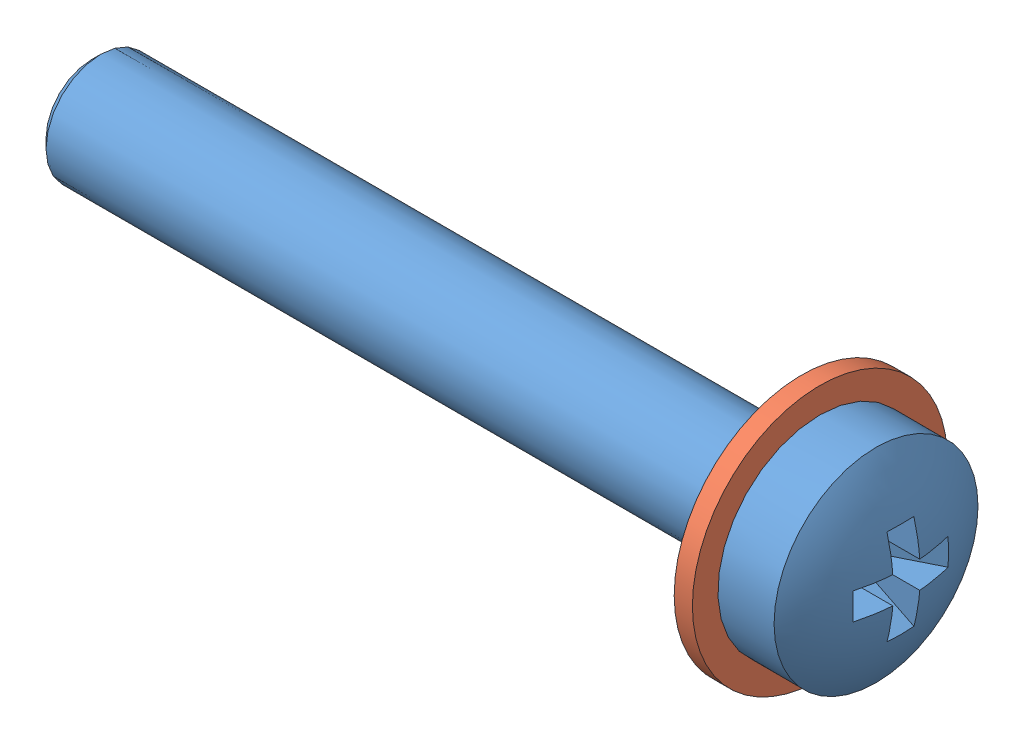
SolidWorks assembly Assembly Screw DIN 7985 - M3 x 20 --- 20N + Washer DIN 125A - M3, configuration Valor predeterminado. Lengths in mm.
Overall size (22.37 7 7).
2 component instances, 2 part files, 2 mates.
Components (placement in the parent):
- Screw DIN 7985 - M3 x 20 --- 20N-1: Screw DIN 7985 - M3 x 20 --- 20N [Valor predeterminado] at (9.8275 -0.3559 22.3725) size (22.37 5.6 5.6)
- Washer DIN 125A - M3-1: Washer DIN 125A - M3 [Valor predeterminado] at (6.9275 -0.3559 22.3725) size (0.5 7 7)
Mates (geometry in assembly coordinates):
- Concêntrico1: concentric: cylinder of assembly; cylinder of assembly; cylinder of Screw DIN 7985 - M3 x 20 --- 20N-1 through (9.8275 -0.3559 22.3725) axis (1 0 0) radius 1.5; cylinder of Washer DIN 125A - M3-1 through (7.4275 -0.3559 22.3725) axis (-1 0 0) radius 1.6
- Coincidente1: coincident: plane of assembly; plane of assembly; plane of Screw DIN 7985 - M3 x 20 --- 20N-1 through (7.4275 1.1441 22.3725) normal (-1 0 0); plane of Washer DIN 125A - M3-1 through (7.4275 -0.3559 22.3725) normal (1 0 0)
